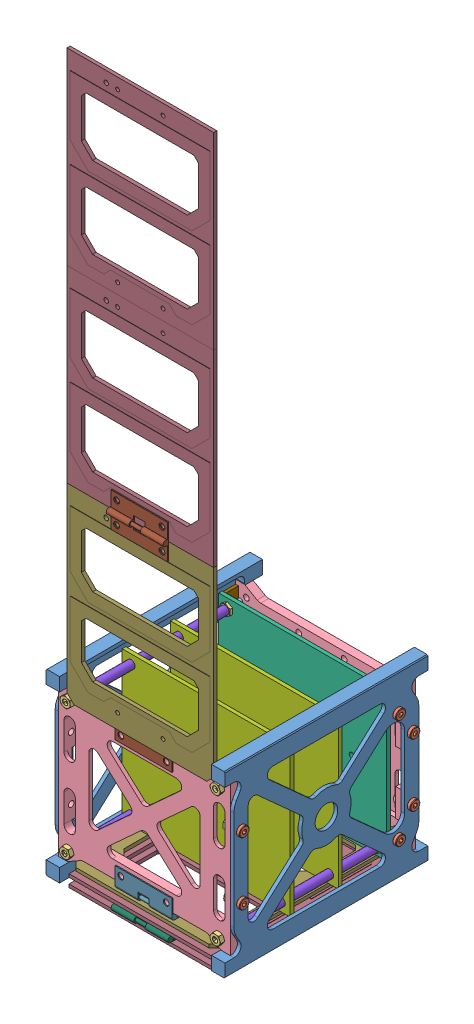
SolidWorks assembly 1U_Chassis, configuration Default. Lengths in mm.
Overall size (102.12 407.52 114.01).
61 component instances, 15 part files, 56 mates.
Components (placement in the parent):
- X-Face-1: X-Face [Default] at (6.5247 99.6979 78.5413) size (7.5 100 113.5)
- X-Face-2: X-Face [Default] at (106.5247 99.6979 78.5413) x (-1 0 0) z (0 0 1) size (7.5 100 113.5)
- 92855A309_18-8 Stainless Steel Low-Profile Socket Head Screws-1: 92855A309_18-8 Stainless Steel Low-Profile Socket Head Screws [92855A309] at (98.5247 117.1979 126.2913) x (0 0 1) z (-1 0 0) size (5.5 5.5 10.17)
- 90685A037_High-Strength Steel Hex Nut-1: 90685A037_High-Strength Steel Hex Nut [90685A037] at (100.3247 117.1979 126.2913) x (0 0 1) z (-1 0 0) size (5.5 6.35 2.69)
- 92855A309_18-8 Stainless Steel Low-Profile Socket Head Screws-2: 92855A309_18-8 Stainless Steel Low-Profile Socket Head Screws [92855A309] at (98.5247 82.1979 126.2913) x (0 0.91884 0.39463) z (-1 0 0) size (5.5 5.5 10.17)
- 90685A037_High-Strength Steel Hex Nut-2: 90685A037_High-Strength Steel Hex Nut [90685A037] at (100.8247 82.1979 126.2913) x (0 -0.924225 -0.381849) z (1 0 0) size (5.5 6.35 2.69)
- 92855A309_18-8 Stainless Steel Low-Profile Socket Head Screws-3: 92855A309_18-8 Stainless Steel Low-Profile Socket Head Screws [92855A309] at (98.5247 117.1979 30.7913) x (0 0.937066 0.349151) z (-1 0 0) size (5.5 5.5 10.17)
- 92855A309_18-8 Stainless Steel Low-Profile Socket Head Screws-4: 92855A309_18-8 Stainless Steel Low-Profile Socket Head Screws [92855A309] at (98.5247 82.1979 30.7913) x (0 0.549538 0.835469) z (-1 0 0) size (5.5 5.5 10.17)
- 90685A037_High-Strength Steel Hex Nut-3: 90685A037_High-Strength Steel Hex Nut [90685A037] at (103.4151 117.1979 30.7913) x (0 0 1) z (-1 0 0) size (5.5 6.35 2.69)
- 90685A037_High-Strength Steel Hex Nut-4: 90685A037_High-Strength Steel Hex Nut [90685A037] at (100.3247 82.1979 30.7913) x (0 0 1) z (-1 0 0) size (5.5 6.35 2.69)
- Z-Face-1: Z-Face [Default] at (56.5247 99.6979 26.7913) x (1 0 0) z (0 -1 0) size (96 8 84.8)
- Z-Face-2: Z-Face [Default] at (56.5247 99.6979 130.2913) x (-1 0 0) z (0 -1 0) size (96 8 84.8)
- 90685A037_High-Strength Steel Hex Nut-5: 90685A037_High-Strength Steel Hex Nut [90685A037] at (14.5247 136.1979 131.4913) x (-0.357096 -0.934068 0) z (0 0 -1) size (5.5 6.35 2.69)
- 90685A037_High-Strength Steel Hex Nut-6: 90685A037_High-Strength Steel Hex Nut [90685A037] at (14.5247 63.1979 131.8682) x (-0.923728 -0.383049 0) z (0 0 -1) size (5.5 6.35 2.69)
- 90685A037_High-Strength Steel Hex Nut-7: 90685A037_High-Strength Steel Hex Nut [90685A037] at (98.5247 136.1979 131.5827) x (-0.923728 -0.383049 0) z (0 0 -1) size (5.5 6.35 2.69)
- 90685A037_High-Strength Steel Hex Nut-8: 90685A037_High-Strength Steel Hex Nut [90685A037] at (98.5247 63.1979 131.646) x (-0.923728 -0.383049 0) z (0 0 -1) size (5.5 6.35 2.69)
- 92855A309_18-8 Stainless Steel Low-Profile Socket Head Screws-5: 92855A309_18-8 Stainless Steel Low-Profile Socket Head Screws [92855A309] at (98.5247 130.1979 38.7913) x (0 -0.400827 -0.916154) z (-1 0 0) size (5.5 5.5 10.17)
- 92855A309_18-8 Stainless Steel Low-Profile Socket Head Screws-6: 92855A309_18-8 Stainless Steel Low-Profile Socket Head Screws [92855A309] at (98.5247 69.1979 38.7913) x (0 0.663174 0.748465) z (-1 0 0) size (5.5 5.5 10.17)
- 90685A037_High-Strength Steel Hex Nut-9: 90685A037_High-Strength Steel Hex Nut [90685A037] at (98.5247 136.1979 41.6536) x (0.999336 0.036432 0) z (0 0 1) size (5.5 6.35 2.69)
- 90685A037_High-Strength Steel Hex Nut-10: 90685A037_High-Strength Steel Hex Nut [90685A037] at (14.5247 136.1979 42.0467) x (-0.999987 -0.005017 0) z (0 0 -1) size (5.5 6.35 2.69)
- 90685A037_High-Strength Steel Hex Nut-11: 90685A037_High-Strength Steel Hex Nut [90685A037] at (14.5247 63.1979 41.6778) x (0.999566 -0.029475 0) z (0 0 1) size (5.5 6.35 2.69)
- 90685A037_High-Strength Steel Hex Nut-12: 90685A037_High-Strength Steel Hex Nut [90685A037] at (98.5247 63.1979 41.599) x (0.999982 0.005949 0) z (0 0 1) size (5.5 6.35 2.69)
- PCB_Stack_3-1: PCB_Stack_3 [Default] at (98.5247 136.1979 34.7913) x (1 -0.000003 0) z (-0.000003 -1 0) size (96 99.53 83)
  - PCB_Rod_2-1: PCB_Rod_2 [Default] at origin size (3 95 3)
  - PCB_Rod_2-2: PCB_Rod_2 [Default] at (-84 0 0.0003) x (-0.139284 0 0.990253) z (-0.990253 0 -0.139284) size (3 95 3)
  - PCB_Rod_2-3: PCB_Rod_2 [Default] at (-83.9998 0 73.0003) x (0.037489 0 0.999297) z (-0.999297 0 0.037489) size (3 95 3)
  - PCB_Rod_2-4: PCB_Rod_2 [Default] at (0.0002 0 73) x (0.981991 0 -0.188925) z (0.188925 0 0.981991) size (3 95 3)
  - PCB_Battery-1: PCB_Battery [Default] at (-41.9999 5 36.5001) x (-1 0 0.000003) z (-0.000003 0 -1) size (94 2 83)
  - PCB-1: PCB [Default] at (-41.9999 59 36.5001) x (1 0 -0.000003) z (0.000003 0 1) size (94 2 83)
  - PCB-2: PCB [Default] at (-41.9999 32 36.5001) x (1 0 -0.000003) z (0.000003 0 1) size (94 2 83)
  - Aluminum Unthreaded Spacer_Battery-1: Aluminum Unthreaded Spacer_Battery [94669A105] at (0 19.5 0) x (0.317635 0 -0.948213) z (0 1 0) size (4.5 4.5 25)
  - Aluminum Unthreaded Spacer_Battery-2: Aluminum Unthreaded Spacer_Battery [94669A105] at (0 46.5 0) x (0.317635 0 -0.948213) z (0 1 0) size (4.5 4.5 25)
  - Aluminum Unthreaded Spacer_Battery-3: Aluminum Unthreaded Spacer_Battery [94669A105] at (0 73.5 0) x (-0.841831 0 -0.539741) z (0 1 0) size (4.5 4.5 25)
  - Aluminum Unthreaded Spacer_Battery-4: Aluminum Unthreaded Spacer_Battery [94669A105] at (0.0002 19.5 73) x (0.317635 0 -0.948213) z (0 1 0) size (4.5 4.5 25)
  - Aluminum Unthreaded Spacer_Battery-5: Aluminum Unthreaded Spacer_Battery [94669A105] at (0.0002 46.5 73) x (0.317635 0 -0.948213) z (0 1 0) size (4.5 4.5 25)
  - Aluminum Unthreaded Spacer_Battery-6: Aluminum Unthreaded Spacer_Battery [94669A105] at (0.0002 73.5 73) x (-0.286549 0 -0.958066) z (0 1 0) size (4.5 4.5 25)
  - Aluminum Unthreaded Spacer_Battery-7: Aluminum Unthreaded Spacer_Battery [94669A105] at (-83.9998 19.5 73.0003) x (0.317635 0 -0.948213) z (0 1 0) size (4.5 4.5 25)
  - Aluminum Unthreaded Spacer_Battery-8: Aluminum Unthreaded Spacer_Battery [94669A105] at (-83.9998 46.5 73.0003) x (0.317635 0 -0.948213) z (0 1 0) size (4.5 4.5 25)
  - Aluminum Unthreaded Spacer_Battery-9: Aluminum Unthreaded Spacer_Battery [94669A105] at (-83.9998 73.5 73.0003) x (-0.883236 0 -0.468929) z (0 1 0) size (4.5 4.5 25)
  - Aluminum Unthreaded Spacer_Battery-10: Aluminum Unthreaded Spacer_Battery [94669A105] at (-84 46.5 0.0003) x (0.317635 0 -0.948213) z (0 1 0) size (4.5 4.5 25)
  - Aluminum Unthreaded Spacer_Battery-11: Aluminum Unthreaded Spacer_Battery [94669A105] at (-84 73.5 0.0003) x (-0.872408 0 -0.488777) z (0 1 0) size (4.5 4.5 25)
  - Aluminum Unthreaded Spacer_Battery-12: Aluminum Unthreaded Spacer_Battery [94669A105] at (-84 19.5 0.0003) x (0.317635 0 -0.948213) z (0 1 0) size (4.5 4.5 25)
  - 88805K144_Architectural 6063 Aluminum 90 Degree Angle-1: 88805K144_Architectural 6063 Aluminum 90 Degree Angle [88805K144] at (-85.2375 0.2375 3.0003) x (-1 0 0.000003) z (0.000003 0 1) size (9.53 9.53 13)
  - 88805K144_Architectural 6063 Aluminum 90 Degree Angle-2: 88805K144_Architectural 6063 Aluminum 90 Degree Angle [88805K144] at (1.2377 0.2375 70) x (0 1 0) z (0.000003 0 1) size (9.53 9.53 13)
  - PCB_Bracket_1_(88805K144_Architectural 6063 Aluminum 90 Degree Angle)-1: PCB_Bracket_1_(88805K144_Architectural 6063 Aluminum 90 Degree Angle) [88805K144] at (1.2375 0.2375 3) x (0 1 0) z (0.000003 0 1) size (9.53 9.53 13)
  - PCB_Bracket_1_(88805K144_Architectural 6063 Aluminum 90 Degree Angle)-2: PCB_Bracket_1_(88805K144_Architectural 6063 Aluminum 90 Degree Angle) [88805K144] at (-85.2373 0.2375 70.0003) x (0 1 0) z (-0.000003 0 -1) size (9.53 9.53 13)
- 90685A037_High-Strength Steel Hex Nut-13: 90685A037_High-Strength Steel Hex Nut [90685A037] at (11.3122 130.1979 38.7913) x (0 0.17998 -0.98367) z (1 0 0) size (5.5 6.35 2.69)
- COTS_OPEN-1: COTS_OPEN [Default] at (85.632 135.5476 144.7949) x (0 1 0) z (-1 0 0) size (323.47 8.13 82)
  - COTS_STS1114_180-1: COTS_STS1114_180 [Default] at (-5.3531 13.9448 13.2324) size (19.13 3.17 31.75)
  - SP_Imperial_COTS_Hinge_BASE-1: SP_Imperial_COTS_Hinge_BASE [Default] at (54.6417 13.9448 29.1074) x (-1 0 0) z (0 -1 0) size (105.41 82 1.98)
  - COTS_STS1114_180-2: COTS_STS1114_180 [Default] at (116.8971 12.1668 13.2324) x (-1 0 0) z (0 0 1) size (19.13 3.17 31.75)
  - Solar_Panel_FULL_Imperial_COTS_Hinge-1: Solar_Panel_FULL_Imperial_COTS_Hinge [Default] at (160.0263 13.9448 29.1074) x (-1 0 0) z (0 -1 0) size (105.41 82 1.98)
  - COTS_STS1114_180-3: COTS_STS1114_180 [Default] at (203.1555 13.9448 13.2324) size (19.13 3.17 31.75)
  - Solar_Panel_FULL_Imperial_COTS_Hinge-2: Solar_Panel_FULL_Imperial_COTS_Hinge [Default] at (265.4109 13.9448 29.1074) x (-1 0 0) z (0 -1 0) size (105.41 82 1.98)
- COTS_CLOSED-1: COTS_CLOSED [Default] at (82.4423 68.1791 105.3111) x (0 -1 0) z (-1 0 0) size (23.06 108.61 82)
  - COTS_STS1114_90-1: COTS_STS1114_90 [Default] at (8.5663 23.9515 10.0426) size (11.18 11.18 31.75)
  - SP_Imperial_COTS_Hinge_BASE-1: SP_Imperial_COTS_Hinge_BASE [Default] at (10.1538 -26.5056 25.9176) x (0 1 0) z (1 0 0) size (105.41 82 1.98)
  - COTS_STS1114_0-1: COTS_STS1114_0 [Default] at (13.5193 -79.2233 41.7926) x (1 0 0) z (0 0 -1) size (3.17 11.18 31.75)
  - Solar_Panel_FULL_Imperial_COTS_Hinge-1: Solar_Panel_FULL_Imperial_COTS_Hinge [Default] at (16.8848 -26.5056 25.9176) x (0 -1 0) z (-1 0 0) size (105.41 82 1.98)
  - COTS_STS1114_0-2: COTS_STS1114_0 [Default] at (18.4723 26.2121 10.0426) size (3.17 11.18 31.75)
  - Solar_Panel_FULL_Imperial_COTS_Hinge-2: Solar_Panel_FULL_Imperial_COTS_Hinge [Default] at (20.0598 -26.5056 25.9176) x (0 1 0) z (1 0 0) size (105.41 82 1.98)
Mates (geometry in assembly coordinates):
- Coincident2: coincident anti-aligned: plane of X-Face-1 through (8.5247 57.1979 135.2913) normal (1 0 0); plane of S2-1 through (8.5247 142.1979 184.9271) normal (-1 0 0)
- Coincident3: coincident anti-aligned: plane of X-Face-1 through (8.5247 142.1979 135.2913) normal (0 -1 0); plane of S2-1 through (56.5247 142.1979 135.6771) normal (0 1 0)
- Coincident5: coincident anti-aligned: plane of S2-1 through (56.5247 142.1979 135.6771) normal (0 1 0); plane of X-Face-2 through (99.0247 142.1979 135.2913) normal (0 -1 0)
- Coincident6: coincident anti-aligned: plane of S2-1 through (104.5247 142.1979 184.9271) normal (1 0 0); plane of X-Face-2 through (104.5247 142.1979 135.2913) normal (-1 0 0)
- Coincident8: coincident anti-aligned: plane of X-Face-1 through (14.0247 57.1979 135.2913) normal (0 1 0); plane of S2-2 through (56.5247 57.1979 135.1691) normal (0 -1 0)
- Coincident9: coincident anti-aligned: plane of X-Face-1 through (8.5247 57.1979 135.2913) normal (1 0 0); plane of S2-2 through (8.5247 59.1979 184.4191) normal (-1 0 0)
- Coincident14: coincident aligned: plane of X-Face-1 through (14.0247 149.6979 135.2913) normal (0 1 0); plane of X-Face-2 through (106.5247 149.6979 135.2913) normal (0 1 0)
- Coincident16: coincident anti-aligned: plane of X-Face-1 through (8.5247 57.1979 135.2913) normal (1 0 0); plane of Z-2 through (8.5247 57.1979 130.2913) normal (-1 0 0)
- Coincident17: coincident aligned: plane of X-Face-1 through (6.5247 99.6979 130.2913) normal (0 0 1); plane of Z-2 through (104.5247 57.1979 130.2913) normal (0 0 1)
- Coincident18: coincident anti-aligned: plane of X-Face-1 through (14.0247 57.1979 135.2913) normal (0 1 0); plane of Z-2 through (56.5247 57.1979 128.2913) normal (0 -1 0)
- Concentric5: concentric aligned: cylinder of X-Face-2 through (106.5247 117.1979 126.2913) axis (-1 0 0) radius 1.5875; cylinder of 92855A309_18-8 Stainless Steel Low-Profile Socket Head Screws-1 through (108.5247 117.1979 126.2913) axis (-1 0 0) radius 2.75
- Coincident19: coincident anti-aligned: plane of X-Face-2 through (106.5247 49.6979 135.2913) normal (1 0 0); plane of 92855A309_18-8 Stainless Steel Low-Profile Socket Head Screws-1 through (106.5247 117.1979 126.2913) normal (-1 0 0)
- Coincident21: coincident anti-aligned: circle of Z-2; circle of 90685A037_High-Strength Steel Hex Nut-1
- Concentric6: concentric aligned: circle of S1-2; circle of 92855A309_18-8 Stainless Steel Low-Profile Socket Head Screws-2
- Concentric7: concentric aligned: cylinder of X-Face-2 through (106.5247 82.1979 126.2913) axis (-1 0 0) radius 1.5875; cylinder of 92855A309_18-8 Stainless Steel Low-Profile Socket Head Screws-2 through (108.5247 82.1979 126.2913) axis (-1 0 0) radius 2.75
- Coincident22: coincident anti-aligned: plane of X-Face-2 through (106.5247 49.6979 135.2913) normal (1 0 0); plane of 92855A309_18-8 Stainless Steel Low-Profile Socket Head Screws-2 through (106.5247 82.1979 126.2913) normal (-1 0 0)
- Coincident23: coincident anti-aligned: circle of Z-2; circle of 90685A037_High-Strength Steel Hex Nut-2
- Concentric8: concentric aligned: cylinder of X-Face-2 through (106.5247 117.1979 30.7913) axis (-1 0 0) radius 1.5875; cylinder of 92855A309_18-8 Stainless Steel Low-Profile Socket Head Screws-3 through (108.5247 117.1979 30.7913) axis (-1 0 0) radius 2.75
- Coincident24: coincident anti-aligned: plane of X-Face-2 through (104.5247 142.1979 135.2913) normal (-1 0 0); plane of Z-2 through (104.5247 57.1979 120.7913) normal (1 0 0)
- Coincident25: coincident anti-aligned: plane of X-Face-2 through (106.5247 49.6979 135.2913) normal (1 0 0); plane of 92855A309_18-8 Stainless Steel Low-Profile Socket Head Screws-3 through (106.5247 117.1979 30.7913) normal (-1 0 0)
- Concentric9: concentric aligned: cylinder of X-Face-2 through (106.5247 82.1979 30.7913) axis (-1 0 0) radius 1.5875; cylinder of 92855A309_18-8 Stainless Steel Low-Profile Socket Head Screws-4 through (108.5247 82.1979 30.7913) axis (-1 0 0) radius 2.75
- Coincident26: coincident anti-aligned: plane of X-Face-2 through (106.5247 49.6979 135.2913) normal (1 0 0); plane of 92855A309_18-8 Stainless Steel Low-Profile Socket Head Screws-4 through (106.5247 82.1979 30.7913) normal (-1 0 0)
- Coincident27: coincident anti-aligned: plane of X-Face-2 through (104.5247 142.1979 135.2913) normal (-1 0 0); plane of Z-Face-1 through (104.5247 57.2979 28.7913) normal (1 0 0)
- Distance1: distance = 0 mm aligned: plane of Z-Face-1 through (90.534 57.8699 26.7913) normal (0 0 -1); plane of X-Face-2 through (106.5247 99.6979 26.7913) normal (0 0 -1)
- Coincident34: coincident aligned: plane of X-Face-1 through (6.5247 99.6979 26.7913) normal (0 0 -1); plane of Z-Face-1 through (90.534 57.8699 26.7913) normal (0 0 -1)
- Coincident35: coincident: plane of Z-Face-1 through (90.534 57.8699 26.7913) normal (0 0 -1); plane of Hinge_Assembly-2/H2-3 through (44.0247 128.9479 26.7913) normal (0 0 1)
- Coincident36: coincident: cylinder of Z-Face-1 through (43.8247 133.7759 28.7913) axis (0 0 -1) radius 1.5875; circle of Hinge_Assembly-2/H2-3
- Parallel3: parallel aligned: line of Z-Face-1 through (90.534 137.5259 26.7913) axis (-1 0 0); line of Hinge_Assembly-2/H2-3 through (79.0247 128.9479 25.0413) axis (-1 0 0)
- Coincident42: coincident anti-aligned: plane of X-Face-1 through (8.5247 57.1979 135.2913) normal (1 0 0); plane of Z-Face-2 through (8.5247 57.2979 128.2913) normal (-1 0 0)
- Coincident43: coincident aligned: plane of X-Face-1 through (6.5247 99.6979 130.2913) normal (0 0 1); plane of Z-Face-2 through (22.5154 57.8699 130.2913) normal (0 0 1)
- Concentric12: concentric anti-aligned: circle of 90685A037_High-Strength Steel Hex Nut-3; circle of Z2-1
- Concentric14: concentric aligned: circle of Z2-2; circle of 90685A037_High-Strength Steel Hex Nut-6
- Concentric15: concentric aligned: circle of Z2-2; circle of 90685A037_High-Strength Steel Hex Nut-7
- Concentric16: concentric aligned: circle of Z2-2; circle of 90685A037_High-Strength Steel Hex Nut-8
- Coincident50: coincident anti-aligned: plane of X-Face-2 through (106.5247 49.6979 135.2913) normal (1 0 0); plane of 92855A309_18-8 Stainless Steel Low-Profile Socket Head Screws-5 through (106.5247 130.1979 38.7913) normal (-1 0 0)
- Coincident51: coincident anti-aligned: plane of X-Face-2 through (106.5247 49.6979 135.2913) normal (1 0 0); plane of 92855A309_18-8 Stainless Steel Low-Profile Socket Head Screws-6 through (106.5247 69.1979 38.7913) normal (-1 0 0)
- Concentric24: concentric aligned: circle of Z-Face-2; circle of 90685A037_High-Strength Steel Hex Nut-5
- Coincident64: coincident anti-aligned: plane of Z-Face-2 through (22.5154 57.8699 130.2913) normal (0 0 1); plane of 90685A037_High-Strength Steel Hex Nut-5 through (14.5247 136.1979 130.2913) normal (0 0 -1)
- Concentric25: concentric anti-aligned: cylinder of X-Face-1 through (6.5247 117.1979 126.2913) axis (1 0 0) radius 1.5875; cylinder of Z-Face-2 through (13.5247 117.1979 126.2913) axis (-1 0 0) radius 1.5875
- Concentric26: concentric anti-aligned: cylinder of Z-Face-2 through (98.5247 63.1979 128.2913) axis (0 0 1) radius 1.5875; cylinder of PCB_Stack_3-1/PCB_Rod_2-4 through (98.5247 63.1979 129.7913) axis (0 0 -1) radius 1.5
- Coincident67: coincident anti-aligned: plane of Z-Face-2 through (56.5247 99.6979 125.7913) normal (0 0 -1); plane of PCB_Stack_3-1/Aluminum Unthreaded Spacer_Battery-3 through (98.5247 136.1979 125.7913) normal (0 0 1)
- Parallel10: parallel anti-aligned: line of X-Face-2 through (104.5247 119.8573 34.7913) axis (0 -1 0); line of PCB_Stack_3-1/PCB_Battery-1 through (103.5247 58.1979 46.7913) axis (0 1 0)
- Concentric27: concentric anti-aligned: circle of 90685A037_High-Strength Steel Hex Nut-10; circle of PCB_Stack_3-1/88805K144_Architectural 6063 Aluminum 90 Degree Angle-1
- Concentric28: concentric anti-aligned: circle of PCB_Stack_3-1/88805K144_Architectural 6063 Aluminum 90 Degree Angle-1; circle of 90685A037_High-Strength Steel Hex Nut-13
- Coincident68: coincident anti-aligned: plane of PCB_Stack_3-1/88805K144_Architectural 6063 Aluminum 90 Degree Angle-1 through (10.1122 126.6979 35.2663) normal (1 0 0); plane of 90685A037_High-Strength Steel Hex Nut-13 through (10.1122 130.1979 38.7913) normal (-1 0 0)
- Coincident69: coincident anti-aligned: circle of 90685A037_High-Strength Steel Hex Nut-9; cylinder of PCB_Stack_3-1/PCB_Rod_2-1 through (98.5247 136.1979 129.7913) axis (0 0 -1) radius 1.5
- Coincident70: coincident anti-aligned: circle of 90685A037_High-Strength Steel Hex Nut-12; cylinder of PCB_Stack_3-1/PCB_Rod_2-4 through (98.5247 63.1979 129.7913) axis (0 0 -1) radius 1.5
- Coincident71: coincident anti-aligned: circle of 90685A037_High-Strength Steel Hex Nut-11; cylinder of PCB_Stack_3-1/PCB_Rod_2-3 through (14.5247 63.1979 129.7913) axis (0 0 -1) radius 1.5
- Concentric29: concentric aligned: circle of X-Face-2; circle of 92855A309_18-8 Stainless Steel Low-Profile Socket Head Screws-5
- Concentric30: concentric aligned: circle of X-Face-2; circle of 92855A309_18-8 Stainless Steel Low-Profile Socket Head Screws-6
- Coincident72: coincident anti-aligned: plane of Z-Face-2 through (22.5154 57.8699 130.2913) normal (0 0 1); plane of COTS_OPEN-1/COTS_STS1114_180-1 through (40.6497 130.1945 130.2913) normal (0 0 -1)
- Concentric31: concentric aligned: cylinder of Z-Face-2 through (43.8247 133.7759 128.2913) axis (0 0 1) radius 1.5875; circle of COTS_OPEN-1/COTS_STS1114_180-1
- Parallel11: parallel aligned: line of Z-Face-2 through (22.5154 137.5259 130.2913) axis (1 0 0); line of COTS_OPEN-1/COTS_STS1114_180-1 through (40.6497 130.1945 130.8501) axis (1 0 0)
- Coincident74: coincident anti-aligned: plane of Z-Face-2 through (22.5154 57.8699 130.2913) normal (0 0 1); plane of COTS_CLOSED-1/COTS_STS1114_90-1 through (40.6497 69.2013 130.2913) normal (0 0 -1)
- Concentric32: concentric aligned: cylinder of Z-Face-2 through (43.8247 65.6199 128.2913) axis (0 0 1) radius 1.5875; circle of COTS_CLOSED-1/COTS_STS1114_90-1
- Parallel12: parallel anti-aligned: line of Z-Face-2 through (90.534 61.8699 130.2913) axis (-1 0 0); line of COTS_CLOSED-1/COTS_STS1114_90-1 through (40.6497 69.2013 130.8501) axis (1 0 0)
